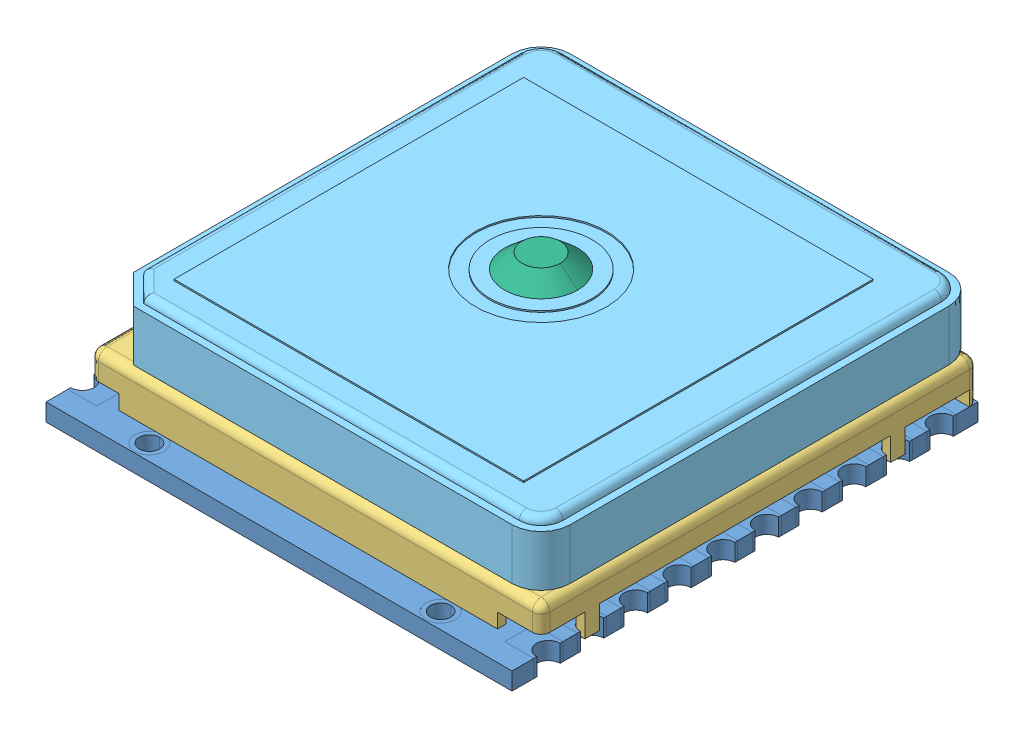
SolidWorks assembly PA6H Assembly.STEP, configuration Défaut. Lengths in mm.
Overall size (16 5.05 16).
6 component instances, 6 part files, 0 mates.
Components (placement in the parent):
- PCB.STEP-1: PCB.STEP [Défaut] at (-10.9011 30.4331 -2.4818) size (16 0.6 16)
- VFBGA-64.STEP-1: VFBGA-64.STEP [Défaut] at (-14.1634 31.2431 0.6572) x (0 0 1) z (0 1 0) size (4.4 4.4 0.96)
- RF Shield.STEP-1: RF Shield.STEP [Défaut] at (-10.4011 32.4331 -2.9818) x (1 0 0) z (0 -1 0) size (15.5 15 1.7)
- Adhesive Pad.STEP-1: Adhesive Pad.STEP [Défaut] at (-10.3911 32.4331 -2.9718) x (0 0 1) z (0 1 0) size (14.5 14.5 0.2)
- Ceramic Antenna.STEP-1: Ceramic Antenna.STEP [Défaut] at (-10.4011 34.3831 -2.9818) x (-1 0 0) z (0 1 0) size (15 15 2.05)
- Rivet.STEP-1: Rivet.STEP [Défaut] at (-10.7011 35.1831 -3.2818) size (2.51 5.05 2.51)
